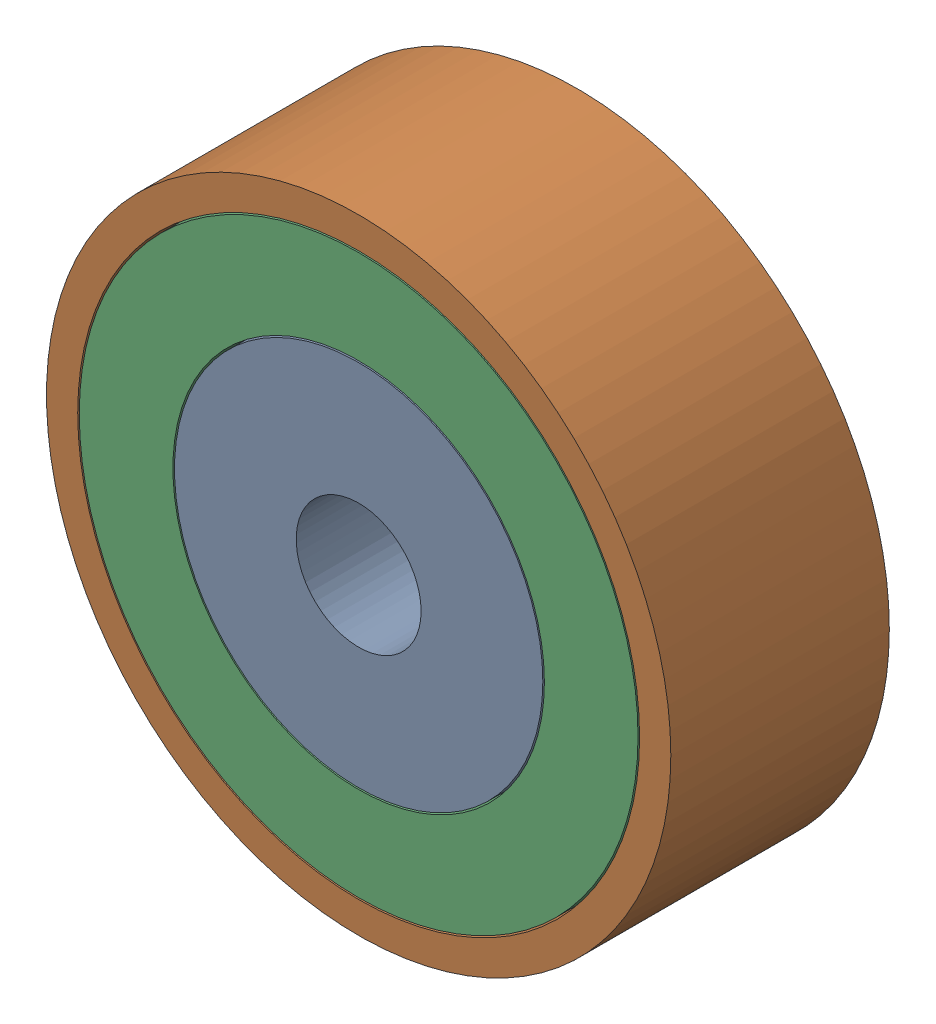
SolidWorks assembly 镜向轴承12, configuration 默认. Lengths in mm.
Overall size (20 20 7).
3 component instances, 3 part files, 4 mates.
Components (placement in the parent):
- 镜向轴承内圈-1: 镜向轴承内圈 [默认] at (-5.0655 0.8032 -6.5) size (11.8 11.8 7)
- 镜向轴承外圈-1: 镜向轴承外圈 [默认] at (-5.0655 0.8032 -6.5) size (20 20 7)
- 镜向轴承中圈-1: 镜向轴承中圈 [默认] at (-5.0655 0.8032 -6.5) size (17.9 17.9 7)
Mates (geometry in assembly coordinates):
- 重合1: coincident: plane of ? through (-5.0655 0.8032 -13.5) normal (0 0 -1); plane of ? through (-5.0655 0.8032 -13.5) normal (0 0 -1)
- 重合2: coincident: plane of ? through (-5.0655 0.8032 -13.5) normal (0 0 -1); plane of ? through (-5.0655 0.8032 -13.5) normal (0 0 -1)
- 同心1: concentric: cylinder of ? through (-5.0655 0.8032 -13.5) axis (0 0 1) radius 9; cylinder of ? through (-5.0655 0.8032 -13.5) axis (0 0 1) radius 8.95
- 同心2: concentric: cylinder of ? through (-5.0655 0.8032 -13.5) axis (0 0 1) radius 5.9; cylinder of ? through (-5.0655 0.8032 -13.5) axis (0 0 1) radius 5.95
